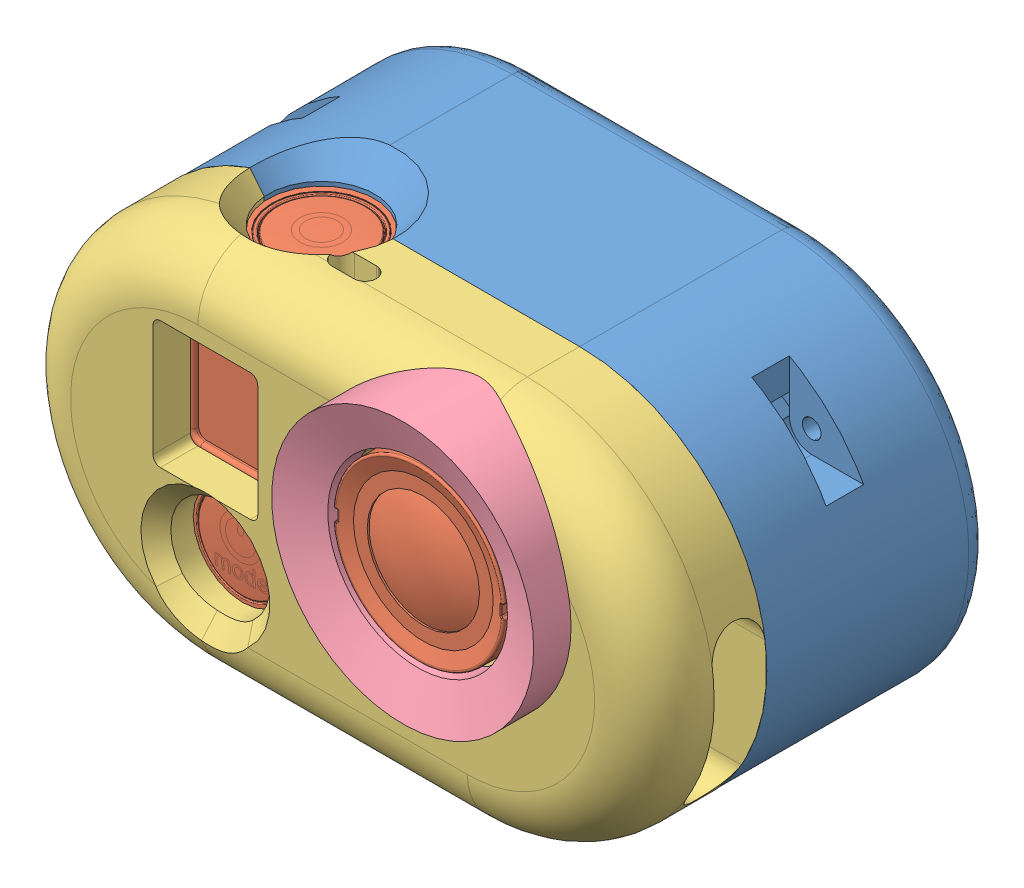
SolidWorks assembly GoProCase_Hero3v1_Assem_v1, configuration Default. Lengths in mm.
Overall size (86 50.24 50).
5 component instances, 5 part files, 6 mates.
Components (placement in the parent):
- BackCase_Hero3_v1-2: BackCase_Hero3_v1 [Default] at origin size (86 50 30)
- GoPro Hero 3-1: GoPro Hero 3 [Default] at (0 0 18.918) size (58.99 41.28 29.67)
- Part3^GoProCase_Hero3v1_Assem_v1-1: Part3^GoProCase_Hero3v1_Assem_v1 [Default] at origin (suppressed, hidden, virtual)
- GoProCase_hero3_Face_v1-1: GoProCase_hero3_Face_v1 [Default] at (0 0 30) size (86 50 15.69)
- GoProCase_hero3_LensCover_v1-1: GoProCase_hero3_LensCover_v1 [Default] at (0 0 30) size (35 35 11.27)
Mates (geometry in assembly coordinates):
- Coincident1: coordinate: point of ?
- Coincident4: coincident: line of BackCase_Hero3_v1-2 through (0 0 0) axis (0 0 1); point of GoPro Hero 3-1
- Coincident5: coincident anti-aligned: plane of BackCase_Hero3_v1-2 through (-18 0 30) normal (0 0 1); plane of GoProCase_hero3_Face_v1-1 through (-18 0 30) normal (0 0 -1)
- Concentric1: concentric aligned: cylinder of BackCase_Hero3_v1-2 through (-18 0 30) axis (0 0 -1) radius 25; cylinder of GoProCase_hero3_Face_v1-1 through (-18 0 45) axis (0 0 -1) radius 25
- Coincident6: coincident anti-aligned: plane of GoProCase_hero3_Face_v1-1 through (-18 0 45) normal (0 0 1); plane of GoProCase_hero3_LensCover_v1-1 through (-18 0 45) normal (0 0 -1)
- Concentric3: concentric aligned: cone of GoPro Hero 3-1 through (14.3572 7.0293 39.873) axis (0 0 1); cylinder of GoProCase_hero3_LensCover_v1-1 through (14.3572 7.0293 46.477) axis (0 0 1) radius 12
